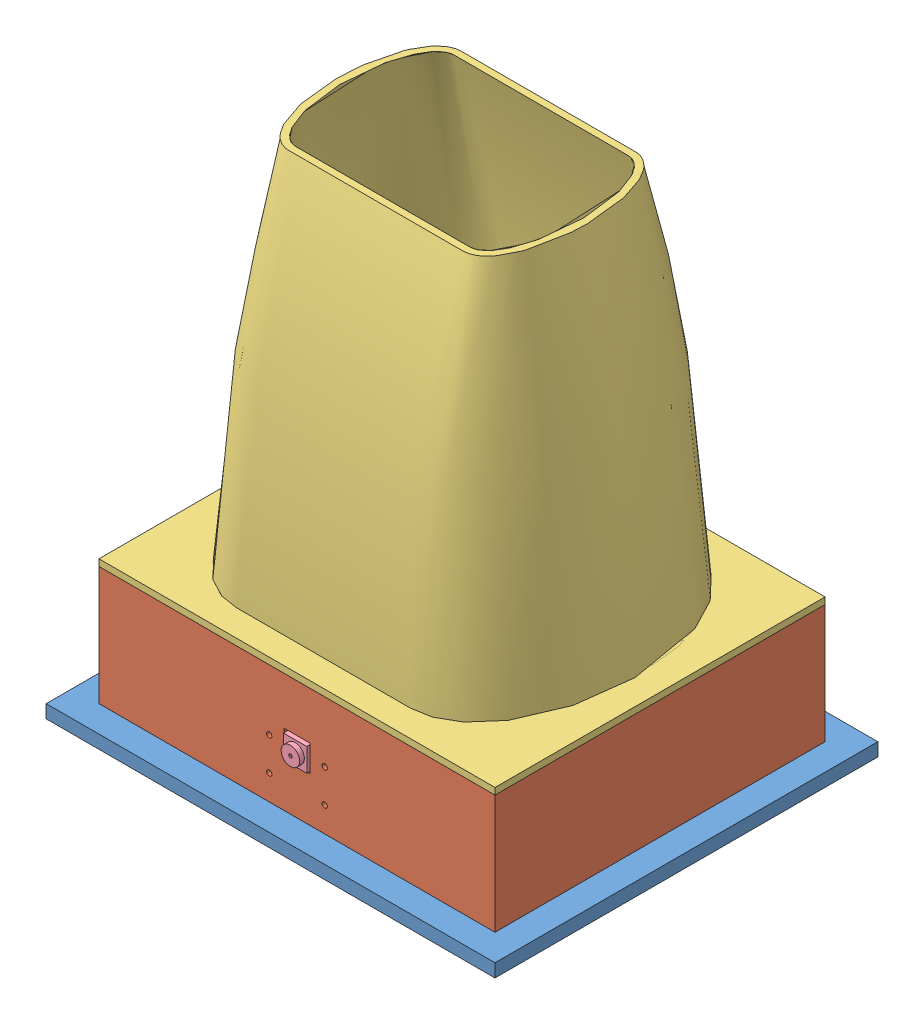
SolidWorks assembly Base Assembly, configuration Default. Lengths in mm.
Overall size (170 72.87 145).
5 component instances, 5 part files, 12 mates.
Components (placement in the parent):
- Base Bottom-2: Base Bottom [Default] at (57.5585 73.6731 141.2736) x (-1 0 0) z (0 0 -1) size (170 20 145)
- Base Middle-1: Base Middle [Default] at (57.5585 76.1731 141.2736) size (150 47.5 125)
- Base Top-1: Base Top [Default] at (57.5585 126.1731 141.2736) x (-1 0 0) z (0 0 -1) size (150 142.51 125)
- Pi Camera-1: Pi Camera [Výchozí] at (57.5585 98.5731 201.2736) size (25.2 33.1 8.7)
- Raspberry Pi 4-2: Raspberry Pi 4 [Default] at (56.6085 81.5731 132.6736) x (0 0 -1) z (1 0 0) size (89 19.92 58.4)
Mates (geometry in assembly coordinates):
- Coincident1: coincident anti-aligned: plane of Base Bottom-2 through (57.5585 76.1731 141.2736) normal (0 1 0); plane of Base Middle-1 through (57.5585 76.1731 141.2736) normal (0 -1 0)
- Coincident2: coincident anti-aligned: plane of Base Bottom-2 through (132.5585 76.1731 203.7736) normal (0 0 -1); plane of Base Middle-1 through (57.5585 123.6731 203.7736) normal (0 0 1)
- Coincident3: coincident anti-aligned: plane of Base Bottom-2 through (-17.4415 76.1731 78.7736) normal (1 0 0); plane of Base Middle-1 through (-17.4415 123.6731 141.2736) normal (-1 0 0)
- Coincident4: coincident anti-aligned: plane of Base Middle-1 through (57.5585 123.6731 141.2736) normal (0 1 0); plane of Base Top-1 through (57.5585 123.6731 141.2736) normal (0 -1 0)
- Coincident5: coincident aligned: plane of Base Middle-1 through (57.5585 123.6731 203.7736) normal (0 0 1); plane of Base Top-1 through (132.5585 123.6731 203.7736) normal (0 0 1)
- Coincident6: coincident aligned: plane of Base Middle-1 through (-17.4415 123.6731 141.2736) normal (-1 0 0); plane of Base Top-1 through (-17.4415 123.6731 78.7736) normal (-1 0 0)
- Coincident10: coincident anti-aligned: plane of Base Middle-1 through (57.5585 123.6731 201.2736) normal (0 0 -1); plane of Pi Camera-1 through (57.5585 98.5731 201.2736) normal (0 0 1)
- Concentric1: concentric anti-aligned: circle of Base Middle-1; circle of Pi Camera-1
- Parallel1: parallel anti-aligned: plane of Base Middle-1 through (52.5585 105.6731 201.2736) normal (0 -1 0); plane of Pi Camera-1 through (57.5585 104.6731 204.4736) normal (0 1 0)
- Coincident11: coincident anti-aligned: plane of Base Bottom-2 through (57.5585 78.6731 141.2736) normal (0 1 0); plane of Raspberry Pi 4-2 through (38.8585 78.6731 87.1736) normal (0 -1 0)
- Distance1: distance = 2.5 mm anti-aligned: plane of Raspberry Pi 4-2 through (28.6085 82.3731 175.1736) normal (0 0 1); plane of Base Bottom-2 through (26.1085 93.6731 177.6736) normal (0 0 -1)
- Distance2: distance = 2.5 mm anti-aligned: plane of Raspberry Pi 4-2 through (28.6085 82.3731 175.1736) normal (-1 0 0); plane of Base Bottom-2 through (26.1085 93.6731 83.7736) normal (1 0 0)
